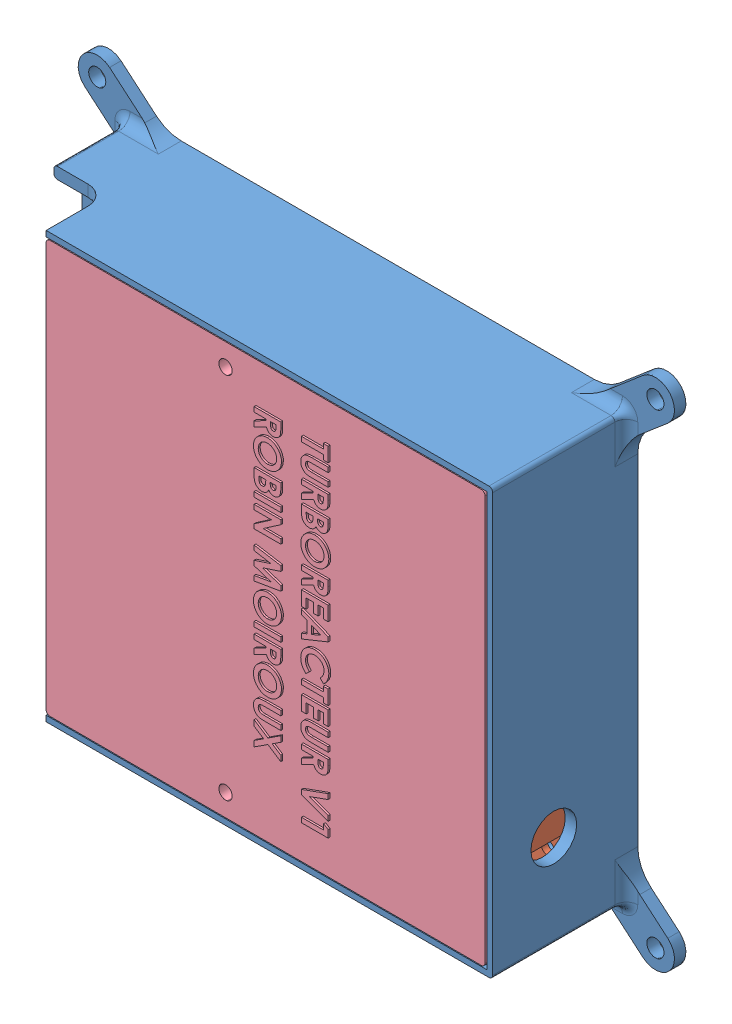
SolidWorks assembly ASM_boitier_electronique, configuration Défaut. Lengths in mm.
Overall size (156.23 134.46 38.5).
4 component instances, 4 part files, 9 mates.
Components (placement in the parent):
- boitier_electronique-1: boitier_electronique [Défaut] at (-7.0435 -8.4337 156.2302) size (156.23 134.46 38)
- carte_turbo-1: carte_turbo [Défaut] at (23.9565 -8.4337 169.2302) x (0 1 0) z (0 0 1) size (94 61 19.6)
- carte_relais-1: carte_relais [Défaut] at (-42.9935 -8.4337 169.2302) x (0 -1 0) z (0 0 1) size (103.5 52.6 16.6)
- couvercle-1: couvercle [Défaut] at (-58.5435 45.5663 191.2302) x (0 -1 0) z (0 0 1) size (108 115 3.5)
Mates (geometry in assembly coordinates):
- Coïncidente1: coincident anti-aligned: plane of boitier_electronique-1 through (49.4565 33.5663 169.2302) normal (0 0 1); plane of carte_turbo-1 through (23.9565 -8.4337 169.2302) normal (0 0 -1)
- Coaxiale1: concentric aligned: cylinder of boitier_electronique-1 through (-1.5435 33.5663 169.2302) axis (0 0 -1) radius 5; cylinder of carte_turbo-1 through (-1.5435 33.5663 170.8302) axis (0 0 -1) radius 1.75
- Coaxiale2: concentric aligned: cylinder of boitier_electronique-1 through (49.4565 -50.4337 169.2302) axis (0 0 -1) radius 5; cylinder of carte_turbo-1 through (49.4565 -50.4337 170.8302) axis (0 0 -1) radius 1.75
- Coaxiale5: concentric aligned: cylinder of boitier_electronique-1 through (-20.4435 39.5663 169.2302) axis (0 0 -1) radius 3.5; cylinder of carte_relais-1 through (-20.4435 39.5663 170.8302) axis (0 0 -1) radius 1.5
- Coïncidente3: coincident anti-aligned: plane of boitier_electronique-1 through (-66.5435 40.5663 169.2302) normal (0 0 1); plane of carte_relais-1 through (-42.9935 -8.4337 169.2302) normal (0 0 -1)
- Coaxiale10: concentric aligned: cylinder of boitier_electronique-1 through (-66.5435 -57.4337 169.2302) axis (0 0 -1) radius 3.5; cylinder of carte_relais-1 through (-66.5435 -57.4337 170.8302) axis (0 0 -1) radius 1.5
- Coïncidente4: coincident anti-aligned: plane of boitier_electronique-1 through (-7.0435 -8.4337 191.2302) normal (0 0 1); plane of couvercle-1 through (-58.5435 45.5663 191.2302) normal (0 0 -1)
- Coaxiale11: concentric aligned: circle of boitier_electronique-1; cylinder of couvercle-1 through (-11.5435 39.8163 194.2302) axis (0 0 -1) radius 1.75
- Coaxiale13: concentric aligned: cone of boitier_electronique-1 through (-11.5435 -56.6837 190.2302) axis (0 0 -1); cylinder of couvercle-1 through (-11.5435 -56.6837 194.2302) axis (0 0 -1) radius 1.75
